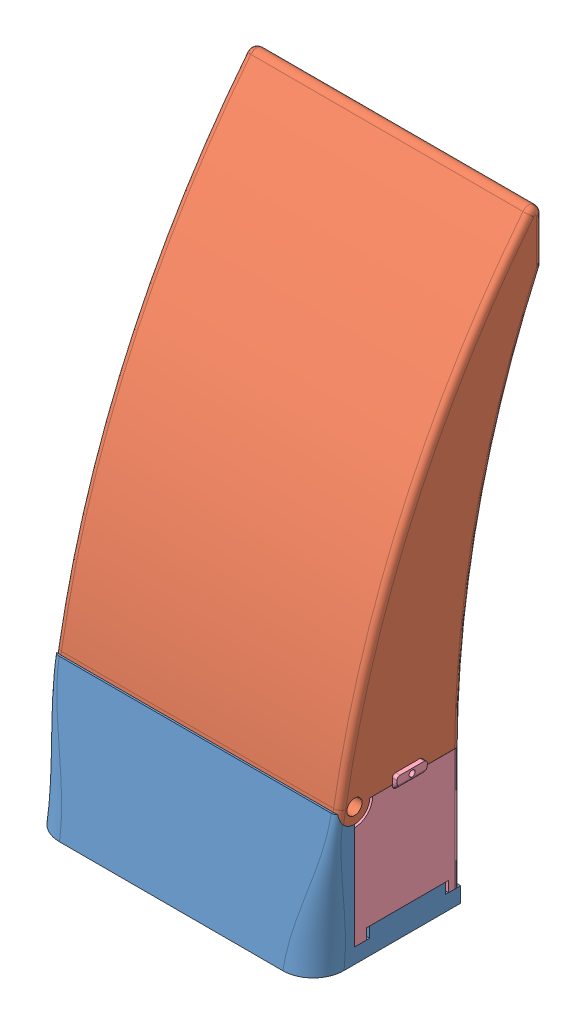
SolidWorks assembly front assembly, configuration Default. Lengths in mm.
Overall size (96.72 188.09 76.48).
4 component instances, 4 part files, 6 mates.
Components (placement in the parent):
- Foldable front base-1: Foldable front base [Default] at (80.0311 10.72 74.0587) size (94.83 52.01 59.18)
- foldable front flap-1: foldable front flap [Default] at (33.1911 55.7084 65.5358) x (-1 0 0) z (0 0.002295 -0.999997) size (94.29 145.94 67.36)
- Foldable front side flap-1: Foldable front side flap [Default] at (-11.1489 19.2191 25.4587) x (0 0 1) z (-1 -0.000934 0) size (35 43 8.5)
- Foldable front side flap left-1: Foldable front side flap left [Default] at (77.5311 19.2206 60.4587) x (0 0 -1) z (1 0.0006 0) size (35 43 8.5)
Mates (geometry in assembly coordinates):
- Distance2: distance = 1 mm: plane of foldable front flap-1 through (75.0311 55.72 60.4587) normal (-1 0 0); plane of Foldable front base-1 through (74.0311 55.72 60.4587) normal (1 0 0)
- Concentric1: concentric: cylinder of Foldable front base-1 through (-21.7911 55.72 60.4587) axis (1 0 0) radius 5; cylinder of foldable front flap-1 through (-8.6489 55.72 60.4587) axis (-1 0 0) radius 5
- Concentric2: concentric: cylinder of Foldable front base-1 through (-10.1489 19.22 55.4587) axis (0 0 -1) radius 2.5; cylinder of Foldable front side flap-1 through (-10.1489 19.22 29.4587) axis (0 0 -1) radius 2.5
- Coincident1: coincident: plane of Foldable front base-1 through (80.0311 10.72 25.4587) normal (0 0 -1); plane of Foldable front side flap-1 through (-13.6489 19.2168 25.4587) normal (0 0 -1)
- Concentric3: concentric: cylinder of Foldable front base-1 through (76.5311 19.22 55.4587) axis (0 0 -1) radius 2.5; cylinder of Foldable front side flap left-1 through (76.5311 19.22 56.4587) axis (0 0 1) radius 2.5
- Coincident2: coincident: plane of Foldable front base-1 through (80.0311 10.72 25.4587) normal (0 0 -1); plane of Foldable front side flap left-1 through (80.0092 55.7221 25.4587) normal (0 0 -1)
